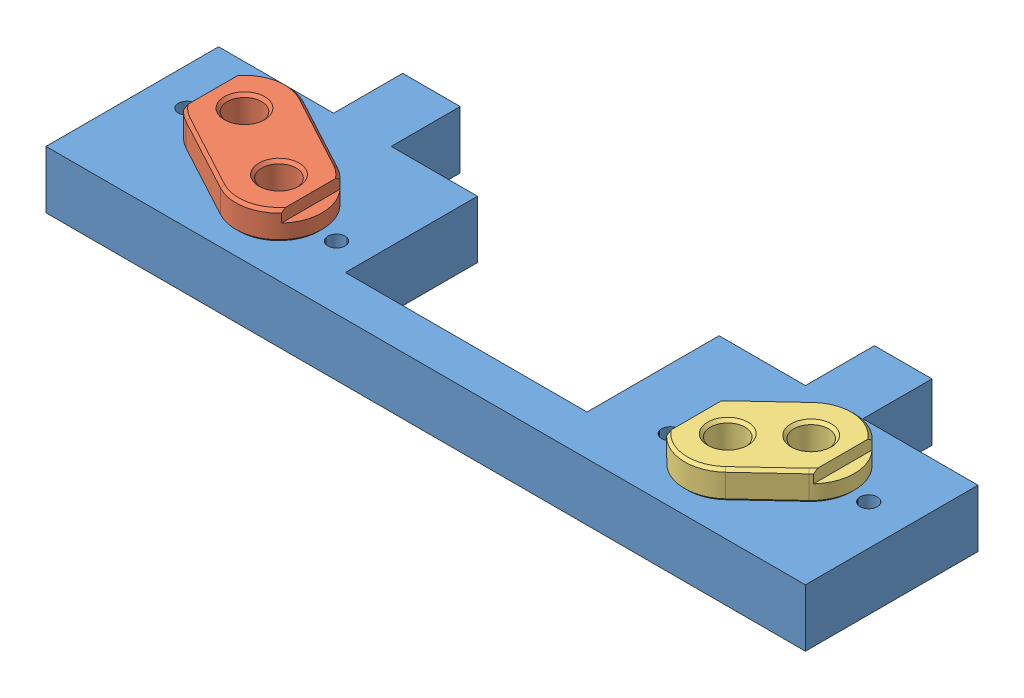
SolidWorks assembly 钻模, configuration 默认. Lengths in mm.
Overall size (264 30 84).
3 component instances, 3 part files, 6 mates.
Components (placement in the parent):
- 钻模板-1: 钻模板 [默认] at (26.2421 85.1817 153.4142) size (264 20 84)
- 特殊钻套1-1: 特殊钻套1 [默认] at (85.2421 85.1817 131.4142) x (1 0 0) z (0 1 0) size (56 44 30)
- 特殊钻套2-1: 特殊钻套2 [默认] at (241.2421 85.1817 131.4142) x (1 0 0) z (0 1 0) size (45 44 30)
Mates (geometry in assembly coordinates):
- 同心1: concentric: cylinder of assembly; cylinder of assembly; cylinder of 钻模板-1 through (85.2421 105.1817 131.4142) axis (0 -1 0) radius 9; cylinder of 特殊钻套1-1 through (85.2421 105.1817 131.4142) axis (0 -1 0) radius 9
- 同心2: concentric: cylinder of assembly; cylinder of assembly; cylinder of 钻模板-1 through (59.2421 105.1817 117.4142) axis (0 -1 0) radius 9; cylinder of 特殊钻套1-1 through (59.2421 105.1817 117.4142) axis (0 -1 0) radius 9
- 重合1: coincident: plane of assembly; plane of assembly; plane of 钻模板-1 through (26.2421 105.1817 153.4142) normal (0 1 0); plane of 特殊钻套1-1 through (85.2421 105.1817 131.4142) normal (0 -1 0)
- 同心3: concentric: cylinder of assembly; cylinder of assembly; cylinder of 钻模板-1 through (241.2421 105.1817 131.4142) axis (0 -1 0) radius 9; cylinder of 特殊钻套2-1 through (241.2421 105.1817 131.4142) axis (0 -1 0) radius 9
- 同心4: concentric: cylinder of assembly; cylinder of assembly; cylinder of 钻模板-1 through (256.2421 105.1817 117.4142) axis (0 -1 0) radius 9; cylinder of 特殊钻套2-1 through (256.2421 105.1817 117.4142) axis (0 -1 0) radius 9
- 重合2: coincident: plane of assembly; plane of assembly; plane of 钻模板-1 through (26.2421 105.1817 153.4142) normal (0 1 0); plane of 特殊钻套2-1 through (241.2421 105.1817 131.4142) normal (0 -1 0)
